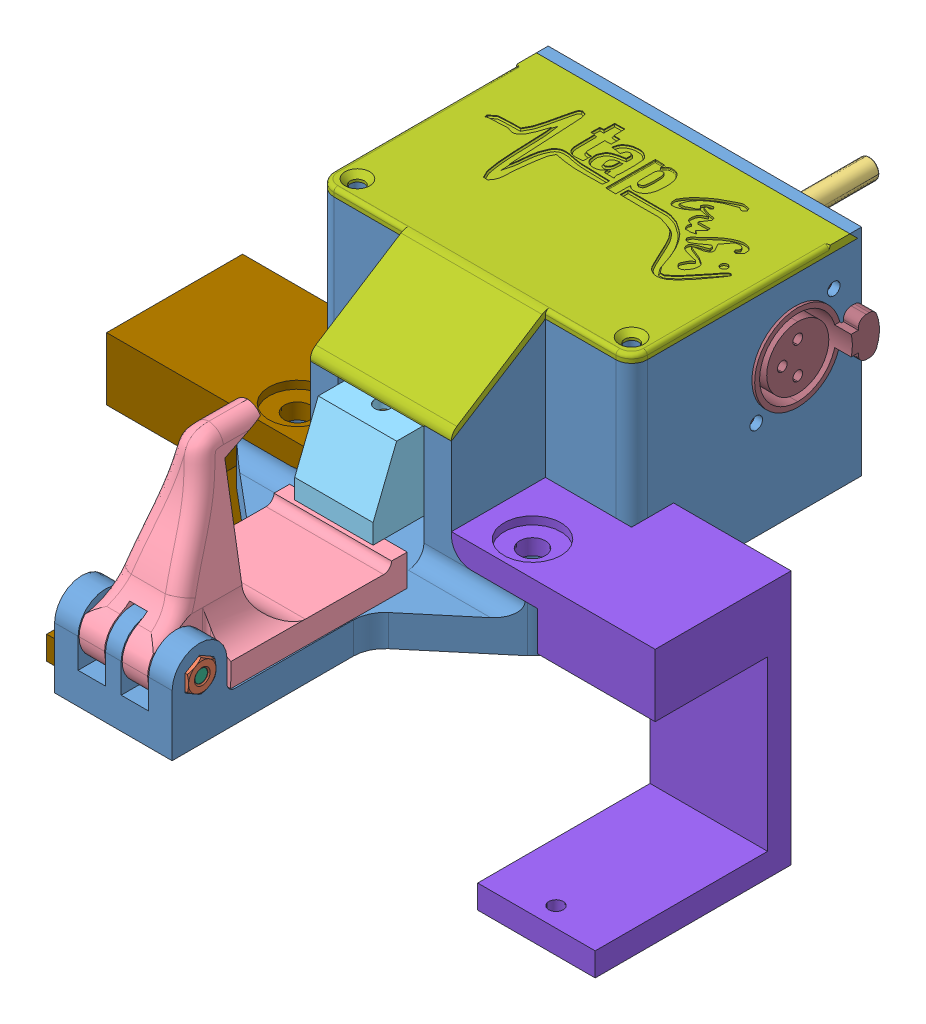
SolidWorks assembly Kabukiv2, configuration Default. Lengths in mm.
Overall size (204 102.97 193.04).
62 component instances, 21 part files, 57 mates.
Components (placement in the parent):
- Base2-1: Base2 [Default] at origin size (80 55 150.98)
- NL3830B-1: NL3830B [Default] at (0 27 -84.1775) size (30 38.01 129.3) (flexible)
  - Case-1: Case [Default] at origin size (30 38.01 64.3)
  - Pin-1: Pin [Default] at (0 0 8.9859) size (15 15.07 129.3)
- Latch2-1: Latch2 [Default] at (0 8.549 0.0487) x (-1 0 0) z (0 -0.006981 -0.999976) size (31.49 47.42 60)
- Notch2-1: Notch2 [Standard] at (-10 17 -76.2916) x (1 0 0) z (0 -1 0) size (30 20 20)
- socket countersunk head screw_din-5: socket countersunk head screw_din [PreviewCfg] at (10 -0.05 -131.4775) x (0 1 0) z (0 0 1) size (8 5.7 5.7)
- socket countersunk head screw_din-6: socket countersunk head screw_din [PreviewCfg] at (-10 -0.05 -131.4775) x (0 1 0) z (0 0 1) size (8 5.7 5.7)
- socket countersunk head screw_din-7: socket countersunk head screw_din [PreviewCfg] at (10 -0.05 -103.4775) x (0 1 0) z (0 0 1) size (8 5.7 5.7)
- Part1^Kabukiv2-1: Part1^Kabukiv2 [Default] at (0 53 0) x (1 0 0) z (0 1 0) size (80 81.7 17.67) (virtual)
- Sidearm-R^Kabukiv2-1: Sidearm-R^Kabukiv2 [Default] at (0 12 0) x (1 0 0) z (0 1 0) size (52 50 65) (virtual)
- MirrorPart4^Kabukiv2-2: MirrorPart4^Kabukiv2 [Default] at (0 12 0) x (-1 0 0) z (0 -1 0) size (52 50 65) (virtual)
- kabuki-pcb-asm-2: kabuki-pcb-asm [Standard] at (-32 46.05 -140.9775) x (1 0 0) z (0 1 0) size (174.7 99.65 36.1)
  - SODFL_SS1FH6^kabuki-pcb-asm-1: SODFL_SS1FH6^kabuki-pcb-asm [Standard] at (36.46 -19.555 1.65) x (1 0 0) z (0 -1 0) size (3.7 1.08 1.81) (virtual)
    - COMPOUND^SODFL_SS1FH6_kabuki-pcb-asm-1: COMPOUND^SODFL_SS1FH6_kabuki-pcb-asm [Standard] at origin size (3.7 1.08 1.81) (virtual)
  - RES0805^kabuki-pcb-asm-1: RES0805^kabuki-pcb-asm [Standard] at (7 -11.5 1.65) x (1 0 0) z (0 -1 0) size (2 0.51 1.26) (virtual)
    - COMPOUND-0^RES0805_kabuki-pcb-asm-1: COMPOUND-0^RES0805_kabuki-pcb-asm [Standard] at origin size (2 0.51 1.26) (virtual)
  - DPAK4P229_FQD18N20V2^kabuki-pcb-asm-1: DPAK4P229_FQD18N20V2^kabuki-pcb-asm [Standard] at (47.97 -25.5 1.65) x (0 1 0) z (1 0 0) size (6.54 2.39 9.91) (virtual)
    - COMPOUND-1^DPAK4P229_FQD18N20V2_kabuki-pcb-asm-1: COMPOUND-1^DPAK4P229_FQD18N20V2_kabuki-pcb-asm [Standard] at origin size (6.54 2.39 9.91) (virtual)
  - RES0805^kabuki-pcb-asm-2: RES0805^kabuki-pcb-asm [Standard] at (55.5 -31 1.65) x (0 1 0) z (1 0 0) size (2 0.51 1.26) (virtual)
    - COMPOUND-0^RES0805_kabuki-pcb-asm-1: COMPOUND-0^RES0805_kabuki-pcb-asm [Standard] at origin size (2 0.51 1.26) (virtual)
  - DPAK4P229_FQD18N20V2^kabuki-pcb-asm-2: DPAK4P229_FQD18N20V2^kabuki-pcb-asm [Standard] at (25.49 -25.5 1.65) x (0 -1 0) z (-1 0 0) size (6.54 2.39 9.91) (virtual)
    - COMPOUND-1^DPAK4P229_FQD18N20V2_kabuki-pcb-asm-1: COMPOUND-1^DPAK4P229_FQD18N20V2_kabuki-pcb-asm [Standard] at origin size (6.54 2.39 9.91) (virtual)
  - nc3fahl1-1^kabuki-pcb-asm-1: nc3fahl1-1^kabuki-pcb-asm [Standard] at (70 -7 -11.05) x (0 0 1) z (-1 0 0) size (27.35 29.5 26.9) (virtual)
    - SOLID^nc3fahl1-1_kabuki-pcb-asm-1: SOLID^nc3fahl1-1_kabuki-pcb-asm [Standard] at origin size (27.35 29.5 26.9) (virtual)
  - d-nc3mahr^kabuki-pcb-asm-1: d-nc3mahr^kabuki-pcb-asm [Standard] at (-6 -7 -11.05) x (0 0 -1) z (1 0 0) size (27.3 25.6 21.5) (virtual)
    - SOLID-2^d-nc3mahr_kabuki-pcb-asm-1: SOLID-2^d-nc3mahr_kabuki-pcb-asm [Standard] at origin size (27.3 25.6 21.5) (virtual)
  - RES0805^kabuki-pcb-asm-3: RES0805^kabuki-pcb-asm [Standard] at (48.5 -18.5 1.65) x (-1 0 0) z (0 1 0) size (2 0.51 1.26) (virtual)
    - COMPOUND-0^RES0805_kabuki-pcb-asm-1: COMPOUND-0^RES0805_kabuki-pcb-asm [Standard] at origin size (2 0.51 1.26) (virtual)
  - RES0805^kabuki-pcb-asm-4: RES0805^kabuki-pcb-asm [Standard] at (52 -18.5 1.65) x (-1 0 0) z (0 1 0) size (2 0.51 1.26) (virtual)
    - COMPOUND-0^RES0805_kabuki-pcb-asm-1: COMPOUND-0^RES0805_kabuki-pcb-asm [Standard] at origin size (2 0.51 1.26) (virtual)
  - RES0805^kabuki-pcb-asm-5: RES0805^kabuki-pcb-asm [Standard] at (7 -18.111 1.65) x (-1 0 0) z (0 1 0) size (2 0.51 1.26) (virtual)
    - COMPOUND-0^RES0805_kabuki-pcb-asm-1: COMPOUND-0^RES0805_kabuki-pcb-asm [Standard] at origin size (2 0.51 1.26) (virtual)
  - RES0805^kabuki-pcb-asm-6: RES0805^kabuki-pcb-asm [Standard] at (21.5 -18.5 1.65) x (1 0 0) z (0 -1 0) size (2 0.51 1.26) (virtual)
    - COMPOUND-0^RES0805_kabuki-pcb-asm-1: COMPOUND-0^RES0805_kabuki-pcb-asm [Standard] at origin size (2 0.51 1.26) (virtual)
  - RES0805^kabuki-pcb-asm-7: RES0805^kabuki-pcb-asm [Standard] at (21.5 -20.5 1.65) x (1 0 0) z (0 -1 0) size (2 0.51 1.26) (virtual)
    - COMPOUND-0^RES0805_kabuki-pcb-asm-1: COMPOUND-0^RES0805_kabuki-pcb-asm [Standard] at origin size (2 0.51 1.26) (virtual)
  - CAP0805^kabuki-pcb-asm-1: CAP0805^kabuki-pcb-asm [Standard] at (7 -20.111 1.65) x (1 0 0) z (0 -1 0) size (2 2 1.25) (virtual)
    - COMPOUND-3^CAP0805_kabuki-pcb-asm-1: COMPOUND-3^CAP0805_kabuki-pcb-asm [Standard] at origin size (2 2 1.25) (virtual)
  - CAP0805^kabuki-pcb-asm-2: CAP0805^kabuki-pcb-asm [Standard] at (7 -14.111 1.65) x (1 0 0) z (0 -1 0) size (2 2 1.25) (virtual)
    - COMPOUND-3^CAP0805_kabuki-pcb-asm-1: COMPOUND-3^CAP0805_kabuki-pcb-asm [Standard] at origin size (2 2 1.25) (virtual)
  - SOIC8P127_IX44XX^kabuki-pcb-asm-1: SOIC8P127_IX44XX^kabuki-pcb-asm [Standard] at (14.5 -16.5 1.65) x (0 -1 0) z (-1 0 0) size (4.91 1.75 6) (virtual)
    - COMPOUND-4^SOIC8P127_IX44XX_kabuki-pcb-asm-1: COMPOUND-4^SOIC8P127_IX44XX_kabuki-pcb-asm [Standard] at origin size (4.91 1.75 6) (virtual)
  - RES0805^kabuki-pcb-asm-8: RES0805^kabuki-pcb-asm [Standard] at (7 -16.111 1.65) x (-1 0 0) z (0 1 0) size (2 0.51 1.26) (virtual)
    - COMPOUND-0^RES0805_kabuki-pcb-asm-1: COMPOUND-0^RES0805_kabuki-pcb-asm [Standard] at origin size (2 0.51 1.26) (virtual)
  - RES0805^kabuki-pcb-asm-9: RES0805^kabuki-pcb-asm [Standard] at (28 -31 1.65) x (0 -1 0) z (-1 0 0) size (2 0.51 1.26) (virtual)
    - COMPOUND-0^RES0805_kabuki-pcb-asm-1: COMPOUND-0^RES0805_kabuki-pcb-asm [Standard] at origin size (2 0.51 1.26) (virtual)
  - SOT23-3P95_MMBZxxxALT1G^kabuki-pcb-asm-1: SOT23-3P95_MMBZxxxALT1G^kabuki-pcb-asm [Standard] at (47 -7 1.65) x (0 1 0) z (1 0 0) size (2.93 1.12 2.37) (virtual)
    - COMPOUND-5^SOT23-3P95_MMBZxxxALT1G_kabuki-pcb-asm-1: COMPOUND-5^SOT23-3P95_MMBZxxxALT1G_kabuki-pcb-asm [Standard] at origin size (2.93 1.12 2.37) (virtual)
  - SOT23-3P95_MMBZxxxALT1G^kabuki-pcb-asm-2: SOT23-3P95_MMBZxxxALT1G^kabuki-pcb-asm [Standard] at (17 -7 1.65) x (0 -1 0) z (-1 0 0) size (2.93 1.12 2.37) (virtual)
    - COMPOUND-5^SOT23-3P95_MMBZxxxALT1G_kabuki-pcb-asm-1: COMPOUND-5^SOT23-3P95_MMBZxxxALT1G_kabuki-pcb-asm [Standard] at origin size (2.93 1.12 2.37) (virtual)
  - CAPPRD750W80D1600H3200^kabuki-pcb-asm-1: CAPPRD750W80D1600H3200^kabuki-pcb-asm [Standard] at (59.5 -31 -0.05) x (0 1 0) z (-1 0 0) size (16.01 34.01 16) (virtual)
    - COMPOUND-6^CAPPRD750W80D1600H3200_kabuki-pcb-asm-1: COMPOUND-6^CAPPRD750W80D1600H3200_kabuki-pcb-asm [Standard] at origin size (16.01 34.01 16) (virtual)
  - CAPPRD750W80D1600H3200^kabuki-pcb-asm-2: CAPPRD750W80D1600H3200^kabuki-pcb-asm [Standard] at (4.5 -31 -0.05) x (0 1 0) z (-1 0 0) size (16.01 34.01 16) (virtual)
    - COMPOUND-6^CAPPRD750W80D1600H3200_kabuki-pcb-asm-1: COMPOUND-6^CAPPRD750W80D1600H3200_kabuki-pcb-asm [Standard] at origin size (16.01 34.01 16) (virtual)
  - CAP0805^kabuki-pcb-asm-3: CAP0805^kabuki-pcb-asm [Standard] at (14.5 -20.5 1.65) x (-1 0 0) z (0 1 0) size (2 2 1.25) (virtual)
    - COMPOUND-3^CAP0805_kabuki-pcb-asm-1: COMPOUND-3^CAP0805_kabuki-pcb-asm [Standard] at origin size (2 2 1.25) (virtual)
  - COMPOUND-7^kabuki-pcb-asm-1: COMPOUND-7^kabuki-pcb-asm [Standard] at origin size (64 40 1.6) (hidden, virtual)
  - kabuki-pcb-1: kabuki-pcb [Standard] at (-102 50 0.7875) size (64 40 1.67)
- socket countersunk head screw_din-1: socket countersunk head screw_din [PreviewCfg] at (-10 -0.05 -103.4775) x (0 1 0) z (0 0 1) size (8 5.7 5.7)
- socket countersunk head screw_din-8: socket countersunk head screw_din [DIN 7991 - M4 x 30 --- 14N] at (-14.6 15.5 -7) x (1 0 0) z (0 -0.326792 0.945096) size (30 7.64 7.64)
- hex nut style 1 gradeab_din-1: hex nut style 1 gradeab_din [Hexagon Nut ISO 4032 - M4 - W - N] at (15.7 15.5 -7) x (0 0.866025 0.5) z (1 0 0) size (7 8.08 3.2)
Mates (geometry in assembly coordinates):
- Coincident1: coordinate: point of Base2-1
- Coincident3: coincident anti-aligned: plane of Base2-1 through (0 8 0) normal (0 1 0); plane of NL3830B-1/Case-1 through (-15 8 -84.1775) normal (0 -1 0)
- Concentric2: concentric anti-aligned: cylinder of Latch2-1 through (-14.8311 15.5 -7) axis (1 0 0) radius 2.15; cylinder of Base2-1 through (-15 15.5 -7) axis (-1 0 0) radius 2.25
- Coincident5: coincident anti-aligned: plane of Latch2-1 through (0 8.549 0.0487) normal (-1 0 0)
- LimitAngle1: limit planar angle = 0.006981 rad anti-aligned: plane of Latch2-1 through (0 8.549 0.0487) normal (0 -0.999976 0.006981); plane of Base2-1 through (0 8 0) normal (0 1 0)
- Coincident7: coincident aligned: plane of NL3830B-1 through (0 27 -84.1775) normal (1 0 0)
- Concentric3: concentric anti-aligned: cylinder of NL3830B-1/Pin-1 through (0 27 -75.6916) axis (0 0 1) radius 7.5; cylinder of Notch2-1 through (0 27 -63.2916) axis (0 0 -1) radius 7.6
- Concentric4: concentric aligned: cylinder of NL3830B-1/Pin-1 through (0 17 -68.6916) axis (0 1 0) radius 2.7599; cylinder of Notch2-1 through (0 11.3431 -68.6916) axis (0 1 0) radius 2
- Coincident8: coincident anti-aligned: plane of NL3830B-1/Case-1 through (15 46 -84.1775) normal (0 1 0); plane of PCB-asm-1/PCB-1 through (0 46 -120.4775) normal (0 -1 0)
- Parallel8: parallel aligned: plane of NL3830B-1/Case-1 through (0 27 -148.4775) normal (0 0 -1); plane of PCB-asm-1/PCB-1 through (35 46 -141.4775) normal (0 0 -1)
- Concentric5: concentric: cylinder of Base2-1 through (40.001 49.9 -130.1) axis (-1 0 0) radius 1.6; cylinder of PCB-asm-1/d-nc3fahr2.stp-1 through (-38 44.9 -130.1) axis (1 0 0) radius 1
- Coincident9: coincident anti-aligned: plane of Base2-1 through (-38 53 0) normal (1 0 0); plane of PCB-asm-1/d-nc3fahr2.stp-1 through (-38 35 -155.385) normal (-1 0 0)
- Coincident10: coincident anti-aligned: plane of Base2-1 through (38 53 0) normal (-1 0 0); plane of PCB-asm-1/nc3mahl-1.stp-1 through (38 35 -129.5037) normal (1 0 0)
- Concentric6: concentric: cylinder of Base2-1 through (-40.001 49.9 -149.9) axis (1 0 0) radius 1.6; cylinder of PCB-asm-1/nc3mahl-1.stp-1 through (38 44.9 -149.9) axis (-1 0 0) radius 1
- Coincident131: coincident aligned: cone of Base2-1 through (-10 0 -103.4775) axis (0 1 0); cone of socket countersunk head screw_din-1 through (-10 0.3 -103.4775) axis (0 1 0)
- Concentric7: concentric anti-aligned: cylinder of Base2-1 through (-15 15.5 -7) axis (-1 0 0) radius 2.25; cone of socket countersunk head screw_din-8 through (-14.12 15.5 -7) axis (1 0 0)
- Concentric9: concentric anti-aligned: cylinder of hex nut style 1 gradeab_din-1 through (-9.3375 15.5 -7) axis (1 0 0) radius 2; cylinder of socket countersunk head screw_din-8 through (-14.6 15.5 -7) axis (-1 0 0) radius 2
- Concentric10: concentric anti-aligned: cylinder of NL3830B-1/Case-1 through (-10 8 -131.4775) axis (0 1 0) radius 1.25; cylinder of PCB-asm-1/PCB-1 through (-10 46 -131.4775) axis (0 -1 0) radius 1.7
- Concentric11: concentric anti-aligned: cylinder of PCB-asm-1/PCB-1 through (-10 46 -131.4775) axis (0 -1 0) radius 1.7; cylinder of socket head cap screw_din-1 through (-10 80.95 -131.4775) axis (0 1 0) radius 1.5
- Coincident18: coincident anti-aligned: plane of PCB-asm-1/PCB-1 through (0 47.6 -120.4775) normal (0 1 0); plane of socket head cap screw_din-1 through (-8.5 47.6 -131.4775) normal (0 -1 0)
- Concentric12: concentric anti-aligned: cylinder of PCB-asm-1/PCB-1 through (10 46 -131.4775) axis (0 -1 0) radius 1.7; cylinder of socket head cap screw_din-2 through (10 80.95 -131.4775) axis (0 1 0) radius 1.5
- Coincident19: coincident anti-aligned: plane of PCB-asm-1/PCB-1 through (0 47.6 -120.4775) normal (0 1 0); plane of socket head cap screw_din-2 through (11.5 47.6 -131.4775) normal (0 -1 0)
- InPlace1: in place: plane of Base2-1 through (0 53 0) normal (0 1 0); plane of Part1^Kabukiv2-1 through (0 53 0) normal (0 1 0); moOrthogonalPlaneRef_w of Base2-1 through (0 53 0) normal (0 1 0); plane of Part1^Kabukiv2-1 through (0 53 0) normal (0 0 -1); plane of Base2-1 through (0 53 0) normal (0 1 0); plane of Part1^Kabukiv2-1 through (0 53 0) normal (1 0 0); plane of Base2-1 through (0 53 0) normal (0 1 0); unknown of Part1^Kabukiv2-1
- Coincident20: coincident aligned: plane of Base2-1; plane of Part1^Kabukiv2-1
- Coincident21: coincident aligned: moOrthogonalPlaneRef_w of Base2-1 through (0 53 0) normal (0 0 -1); plane of Part1^Kabukiv2-1 through (0 53 0) normal (0 0 -1)
- Coincident22: coincident anti-aligned: moOrthogonalPlaneRef_w of Base2-1 through (0 53 0) normal (-1 0 0); plane of Part1^Kabukiv2-1 through (0 53 0) normal (1 0 0)
- LimitDistance1: limit distance = 2.0128 mm anti-aligned: plane of Notch2-1 through (-10 17 -74.2916) normal (0 0 1); plane of Base2-1 through (-16 38 -72.2788) normal (0 0 -1)
- Coincident132: coincident anti-aligned: plane of PCB-asm-1/PCB-1 through (0 46 -120.4775) normal (0 -1 0); plane of d-nc3mahr.stp-1 through (-38 46 -140.5775) normal (0 1 0)
- Coincident134: coincident anti-aligned: plane of PCB-asm-1/PCB-1 through (0 46 -120.4775) normal (0 -1 0); plane of nc3fahl1-1.stp-1 through (38 46 -128.0403) normal (0 1 0)
- Concentric15: concentric anti-aligned: cylinder of Base2-1 through (-40.001 44.9 -143.8775) axis (1 0 0) radius 1.6; cylinder of nc3fahl1-1.stp-1 through (38 44.9 -143.8775) axis (-1 0 0) radius 1
- Coincident136: coincident anti-aligned: plane of Base2-1 through (38 53 0) normal (-1 0 0); plane of nc3fahl1-1.stp-1 through (38 35 -133.9775) normal (1 0 0)
- Concentric16: concentric anti-aligned: cylinder of Base2-1 through (40.001 25.1 -143.8775) axis (-1 0 0) radius 1.6; cylinder of d-nc3mahr.stp-1 through (-38 25.1 -143.8775) axis (1 0 0) radius 1
- Coincident137: coincident anti-aligned: plane of Base2-1 through (-38 53 0) normal (1 0 0); plane of d-nc3mahr.stp-1 through (-38 35 -133.9775) normal (-1 0 0)
- Distance1: distance = 3.5 mm anti-aligned: cylinder of PCB-asm-1/Cap-EL18x36-7_5T-1 through (-27.5 9 -107.2177) axis (0 1 0) radius 9; plane of NL3830B-1/Case-1 through (-15 46 -84.1775) normal (-1 0 0)
- Distance2: distance = 2 mm anti-aligned: cylinder of PCB-asm-1/Cap-EL18x36-7_5T-1 through (-27.5 9 -107.2177) axis (0 1 0) radius 9; cylinder of d-nc3mahr.stp-1 through (-38 44.9 -124.0775) axis (1 0 0) radius 2.9
- Distance3: distance = 3.5 mm anti-aligned: cylinder of PCB-asm-1/Cap-EL18x36-7_5T-2 through (27.5 9 -107.969) axis (0 1 0) radius 9; plane of NL3830B-1/Case-1 through (15 8 -84.1775) normal (1 0 0)
- Distance4: distance = 2 mm anti-aligned: cylinder of PCB-asm-1/Cap-EL18x36-7_5T-2 through (27.5 9 -107.969) axis (0 1 0) radius 9; cylinder of nc3fahl1-1.stp-1 through (38 25.1 -124.0775) axis (-1 0 0) radius 2.95
- Distance5: distance = 0.5 mm anti-aligned: plane of Base2-1 through (0 53 -148.9775) normal (0 0 1); plane of NL3830B-1/Case-1 through (0 27 -148.4775) normal (0 0 -1)
- Coincident139: coincident aligned: cone of Base2-1 through (-15 15.5 -7) axis (1 0 0); cone of socket countersunk head screw_din-8 through (-14.12 15.5 -7) axis (1 0 0)
- Coincident140: coincident anti-aligned: plane of Base2-1 through (12.5 0 0) normal (1 0 0); plane of hex nut style 1 gradeab_din-1 through (12.5 13.4793 -3.5) normal (-1 0 0)
- Parallel10: parallel anti-aligned: plane of Base2-1 through (12.5 13.3349 -10.75) normal (0 0 1); plane of hex nut style 1 gradeab_din-1 through (12.5 13.4793 -10.5) normal (0 0 -1)
- Parallel11: parallel: plane of NL3830B-1/Case-1 through (15 46 -84.1775) normal (0 1 0); plane of Kabuki.step-1/COMPOUND-7.step-1 through (-2.4318 46.05 -120.732) normal (0 -1 0)
- Concentric17: concentric: cylinder of Base2-1 through (40.001 44.9 -124.0775) axis (-1 0 0) radius 1.6; cylinder of Kabuki.step-1/d-nc3mahr.step-1/SOLID.step-1 through (-40.4318 44.9 -124.0775) axis (1 0 0) radius 1
- Coincident141: coincident anti-aligned: plane of Base2-1 through (38 53 0) normal (-1 0 0); plane of Kabuki.step-1/nc3fahl1-1.step-1/SOLID-4.step-1 through (38 35 -133.9775) normal (1 0 0)
- Concentric19: concentric aligned: cylinder of Base2-1 through (-30 -0.001 -76.9775) axis (0 1 0) radius 3.85; cylinder of flange-1 through (-30 0 -76.9775) axis (0 1 0) radius 3.3
- Concentric20: concentric aligned: cylinder of Base2-1 through (30 -0.001 -76.9775) axis (0 1 0) radius 3.85; cylinder of flange-1 through (30 0 -76.9775) axis (0 1 0) radius 3.3
- Coincident142: coincident anti-aligned: plane of Base2-1 through (0 0 0) normal (0 -1 0); plane of flange-1 through (40 0 -61.9775) normal (0 1 0)
- Concentric21: concentric aligned: cylinder of Base2-1 through (30 -0.001 -76.9775) axis (0 1 0) radius 3.85; cylinder of socket head cap screw 4762_din-1 through (30 47.75 -76.9775) axis (0 1 0) radius 5
- Coincident143: coincident anti-aligned: plane of Base2-1 through (30 10 -76.9775) normal (0 1 0); plane of socket head cap screw 4762_din-1 through (35 10 -76.9775) normal (0 -1 0)
- Concentric22: concentric anti-aligned: cylinder of flange-1 through (20 -70.3238 -89.4775) axis (0 1 0) radius 3.65; cylinder of socket head cap screw 4762_din-2 through (20 -97.75 -89.4775) axis (0 -1 0) radius 5
- Coincident144: coincident anti-aligned: plane of flange-1 through (40 -60 -101.9775) normal (0 -1 0); plane of socket head cap screw 4762_din-2 through (15 -60 -89.4775) normal (0 1 0)
- InPlace2: in place: plane of Base2-1 through (0 12 0) normal (0 1 0); plane of Sidearm-R^Kabukiv2-1 through (0 12 0) normal (0 1 0); plane of Base2-1 through (0 12 0) normal (0 1 0); plane of Sidearm-R^Kabukiv2-1 through (0 12 0) normal (0 0 -1); plane of Base2-1 through (0 12 0) normal (0 1 0); plane of Sidearm-R^Kabukiv2-1 through (0 12 0) normal (1 0 0); plane of Base2-1 through (0 12 0) normal (0 1 0); unknown of Sidearm-R^Kabukiv2-1
- Coincident145: coincident aligned: plane of Base2-1; plane of Sidearm-R^Kabukiv2-1
- Coincident146: coincident aligned: moOrthogonalPlaneRef_w of Base2-1 through (0 12 0) normal (0 0 -1); plane of Sidearm-R^Kabukiv2-1 through (0 12 0) normal (0 0 -1)
- Coincident147: coincident anti-aligned: moOrthogonalPlaneRef_w of Base2-1 through (0 12 0) normal (-1 0 0); plane of Sidearm-R^Kabukiv2-1 through (0 12 0) normal (1 0 0)
- Konzentrisch1: concentric anti-aligned: cylinder of Base2-1 through (40.001 44.9 -124.0775) axis (-1 0 0) radius 1.6; cylinder of kabuki-pcb-asm-2/d-nc3mahr^kabuki-pcb-asm-1/SOLID-2^d-nc3mahr_kabuki-pcb-asm-1 through (-38 44.9 -124.0775) axis (1 0 0) radius 1
- Deckungsgleich2: coincident anti-aligned: plane of Base2-1 through (-38 53 0) normal (1 0 0); plane of kabuki-pcb-asm-2/d-nc3mahr^kabuki-pcb-asm-1/SOLID-2^d-nc3mahr_kabuki-pcb-asm-1 through (-38 35 -133.9775) normal (-1 0 0)
